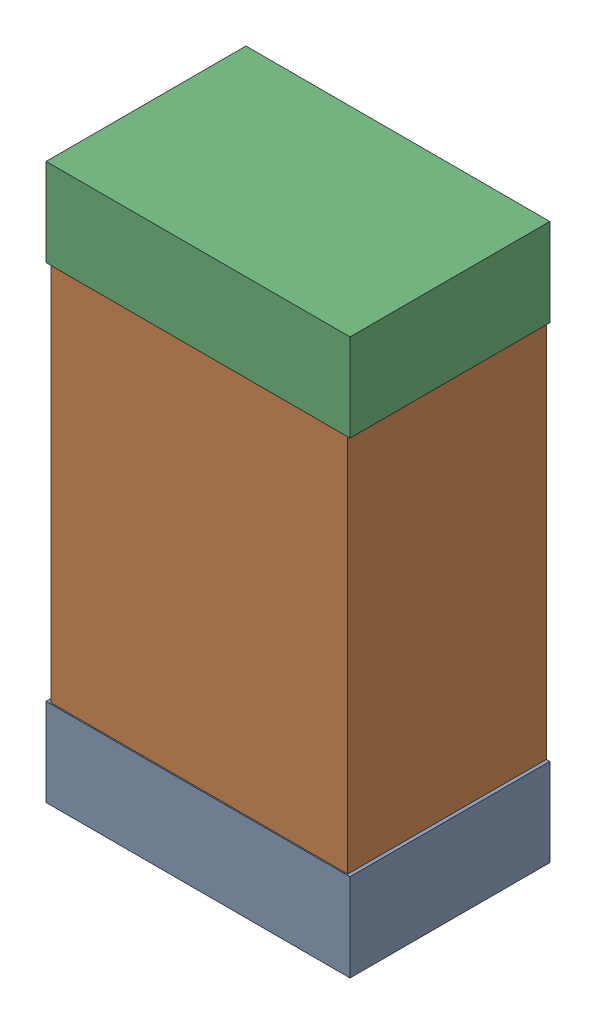
SolidWorks assembly R7Kanaloa_v2.0.0_Power, configuration Default. Lengths in mm.
Overall size (1.3 2.38 0.85).
6 component instances, 2 part files, 0 mates.
Components (placement in the parent):
- 330415056-1: 330415056 [Default] at (72.375 92.85 0) size (1.3 0.38 0.85)
  - Extruded_2-1: Extruded_2 [Default] at origin size (1.3 0.38 0.85)
- 352877008-1: 352877008 [Default] at (72.375 93.85 0) size (1.27 2.2 0.85)
  - Extruded_3-1: Extruded_3 [Default] at origin size (1.27 2.2 0.85)
- 330415056-2: 330415056 [Default] at (72.375 94.85 0) size (1.3 0.38 0.85)
  - Extruded_2-1: Extruded_2 [Default] at origin size (1.3 0.38 0.85)
